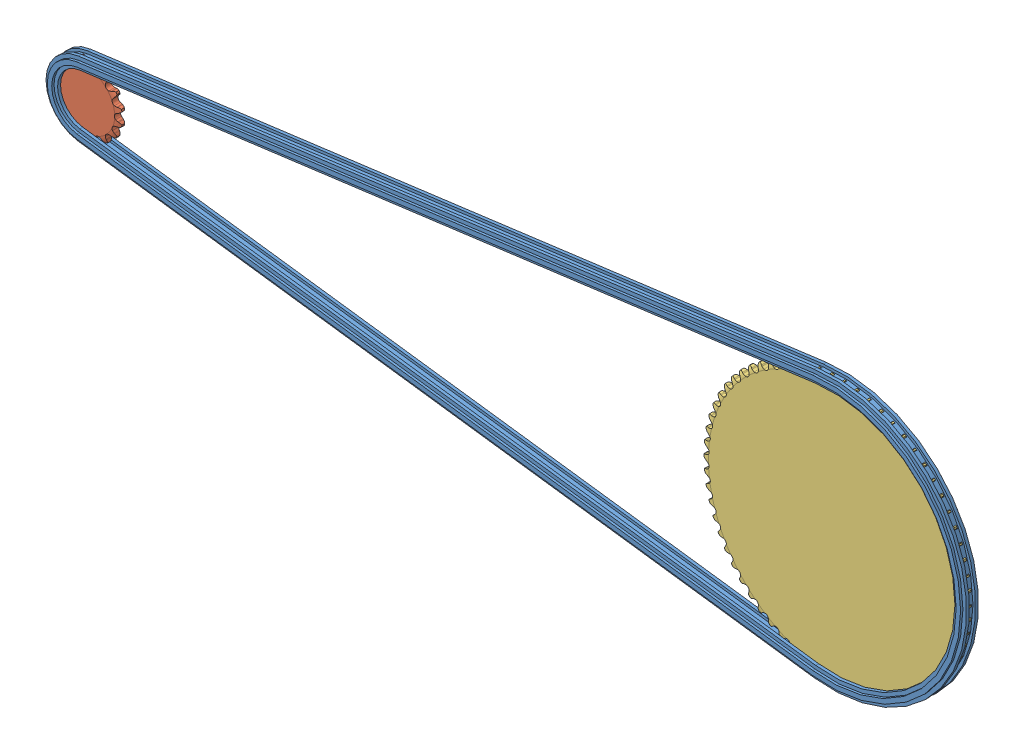
SolidWorks assembly chain drive1, configuration Default. Lengths in mm.
Overall size (476.22 139.45 8.64).
3 component instances, 3 part files, 0 mates.
Components (placement in the parent):
- Roller Chain-11-1: Roller Chain-11 [Default] at (280.5916 -228.011 -328.0371) size (476.22 139.45 8.64)
- Roller Chain Sprocket1-11-1: Roller Chain Sprocket1-11 [Default] at (20.3714 -228.011 -328.0371) size (35.23 35.23 3.68)
- Roller Chain Sprocket2-11-1: Roller Chain Sprocket2-11 [Default] at (407.5916 -228.011 -328.0371) size (137.11 136.99 3.98)
